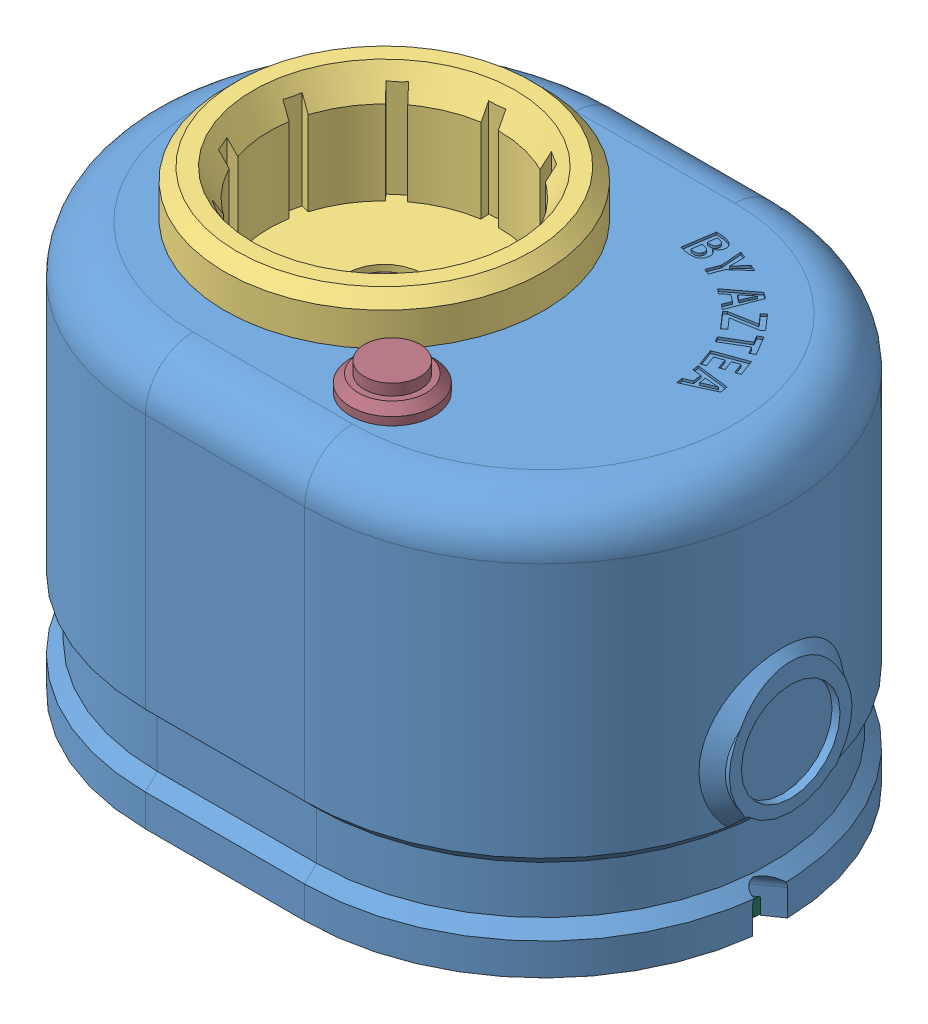
SolidWorks assembly Assem, configuration Default. Lengths in mm.
Overall size (81.48 58.5 65.83).
19 component instances, 16 part files, 39 mates.
Components (placement in the parent):
- Shell-1: Shell [Default] at origin size (81.48 51 60)
- deep groove ball bearings gb-1: deep groove ball bearings gb [Rolling bearings 619-5 GB 276-94] at (0 19 0) x (0 1 0) z (-0.056348 0 0.998411) size (4 13 13)
- deep groove ball bearings gb-2: deep groove ball bearings gb [Rolling bearings 619-9 GB 276-94] at (0 33 0) x (0 1 0) z (0 0 1) size (6 20 20)
- Base-1: Base [Default] at (0 30 0) x (-0.082229 0 -0.996613) z (0.996613 0 -0.082229) size (40 27 40)
- Screw-1: Screw [Default] at (0 39 0) size (9 36.5 9)
- Motor-2: Motor [Default] at (31 22.2 0) x (-1 0 0) z (0 0 -1) size (32 35.4 47)
- Crank_M-1: Crank_M [Default] at (23 9 0) x (-0.933743 0 -0.357945) z (0.357945 0 -0.933743) size (18.5 7 10)
- Rocker_B-1: Rocker_B [Default] at (0 7 0) x (-0.082229 0 -0.996613) z (0.996613 0 -0.082229) size (31 10 12)
- Link-1: Link [Default] at (-1.5624 3 -18.9357) x (0.72285 0 0.691005) z (-0.691005 0 0.72285) size (33 6 10)
- ScrewM3-1: ScrewM3 [Default] at (-1.5624 6.5 -18.9357) x (0.991725 0 -0.128382) z (-0.128382 0 -0.991725) size (7 14.5 7)
- ScrewM3-2: ScrewM3 [Default] at (15.0632 6.5 -3.0425) x (-0.517907 0 -0.855437) z (-0.855437 0 0.517907) size (7 14.5 7)
- NutM3_FS-1: NutM3_FS [Default] at (15.0632 12 -3.0425) x (0.776861 0 -0.629672) z (0.629672 0 0.776861) size (6.29 3.9 5.5)
- NutM3_FS-2: NutM3_FS [Default] at (-1.5624 13 -18.9357) x (0.904207 0 0.427094) z (-0.427094 0 0.904207) size (6.29 3.9 5.5)
- NutM4_FS-2: NutM4_FS [Default] at (0 12 0) x (0.821978 0 -0.569519) z (-0.569519 0 -0.821978) size (8.02 5 7)
- Bushing-1: Bushing [Default] at (0 -13.7901 0) x (0.95303 0 0.302877) z (-0.302877 0 0.95303) size (12.8 9 12.8)
- Switch-1: Switch [Default] at (19 54.4 18) x (0 -1 0) z (-0.091572 0 0.995798) size (21.9 10.5 10.5)
- NutM8-2: NutM8 [Default] at (19 49 18) x (0.969422 0 -0.245401) z (0 -1 0) size (9.9 11.43 2.2)
- BasePlate-1: BasePlate [Default] at origin size (75.8 22 55.8)
- BaseSupport-1: BaseSupport [Default] at origin size (59.67 1.5 46.11)
Mates (geometry in assembly coordinates):
- Concentric1: concentric anti-aligned: cylinder of Shell-1 through (0 36 0) axis (0 1 0) radius 6.5; cylinder of Rolling bearings 619-5 GB 276-94-1 through (0 10.2893 0) axis (0 -1 0) radius 6.5
- Coincident1: coincident anti-aligned: plane of Shell-1 through (-6.5 21 0) normal (0 -1 0); plane of Rolling bearings 619-5 GB 276-94-1 through (-6.4897 21 -0.3663) normal (0 1 0)
- Concentric2: concentric anti-aligned: cylinder of Shell-1 through (0 36 0) axis (0 1 0) radius 10; cylinder of Rolling bearings 619-9 GB 276-94-1 through (0 24.2893 0) axis (0 -1 0) radius 10
- Coincident2: coincident anti-aligned: plane of Shell-1 through (-8 30 0) normal (0 1 0); plane of Rolling bearings 619-9 GB 276-94-1 through (-10 30 0) normal (0 -1 0)
- Concentric3: concentric anti-aligned: cylinder of Shell-1 through (0 -9 0) axis (0 1 0) radius 18; cylinder of Base-1 through (0 30 0) axis (0 -1 0) radius 14.5
- Coincident3: coincident anti-aligned: plane of Rolling bearings 619-9 GB 276-94-1 through (-4.5 36 0) normal (0 1 0); plane of Base-1 through (0.5345 36 6.478) normal (0 -1 0)
- Concentric4: concentric anti-aligned: cylinder of Base-1 through (0 30 0) axis (0 -1 0) radius 2.5; cylinder of Screw-1 through (0 42.5 0) axis (0 1 0) radius 2.5
- Coincident4: coincident anti-aligned: plane of Base-1 through (0.2056 39 2.4915) normal (0 1 0); plane of Screw-1 through (-4.5 39 0) normal (0 -1 0)
- Concentric8: concentric aligned: cylinder of Motor-2 through (23 22.2 0) axis (0 1 0) radius 2.5; cylinder of Crank_M-1 through (23 12 0) axis (0 1 0) radius 2.5
- Coincident8: coincident anti-aligned: plane of Motor-2 through (25.5 12 0) normal (0 -1 0); plane of Crank_M-1 through (23 12 0) normal (0 1 0)
- Distance1: distance = 31 mm anti-aligned: plane of Motor-2 through (31 22.2 0) normal (-1 0 0)
- Distance2: distance = 1.6 mm anti-aligned: plane of Motor-2 through (43.25 47.4 0) normal (0 1 0); plane of Shell-1 through (0 49 0) normal (0 -1 0)
- Coincident12: coincident anti-aligned: plane of Motor-2 through (31 22.2 0) normal (0 0 -1)
- Concentric9: concentric anti-aligned: cylinder of Screw-1 through (0 42.5 0) axis (0 1 0) radius 2.5; cylinder of Rocker_B-1 through (0 7 0) axis (0 -1 0) radius 2.55
- Coincident13: coincident anti-aligned: plane of Rolling bearings 619-5 GB 276-94-1 through (-3.8272 17 -0.216) normal (0 -1 0); plane of Rocker_B-1 through (0 17 0) normal (0 1 0)
- Concentric10: concentric aligned: cylinder of Rocker_B-1 through (-1.5624 7 -18.9357) axis (0 -1 0) radius 2.075; cylinder of Link-1 through (-1.5624 9 -18.9357) axis (0 -1 0) radius 5
- Concentric11: concentric aligned: cylinder of Crank_M-1 through (15.0632 9 -3.0425) axis (0 -1 0) radius 2.075; cylinder of Link-1 through (15.0632 9 -3.0425) axis (0 -1 0) radius 5
- Concentric12: concentric aligned: cylinder of Link-1 through (-1.5624 3 -18.9357) axis (0 -1 0) radius 2.075; cylinder of ScrewM3-1 through (-1.5624 3 -18.9357) axis (0 -1 0) radius 2
- Coincident15: coincident anti-aligned: plane of Link-1 through (-4.273 6.5 -21.5269) normal (0 -1 0); plane of ScrewM3-1 through (-5.0334 6.5 -18.4863) normal (0 1 0)
- Concentric13: concentric aligned: cylinder of Link-1 through (15.0632 3 -3.0425) axis (0 -1 0) radius 2.075; cylinder of ScrewM3-2 through (15.0632 3 -3.0425) axis (0 -1 0) radius 2
- Coincident16: coincident anti-aligned: plane of Link-1 through (12.3525 6.5 -5.6338) normal (0 -1 0); plane of ScrewM3-2 through (16.8759 6.5 -0.0485) normal (0 1 0)
- Concentric14: concentric aligned: cylinder of ScrewM3-1 through (-1.5624 3 -18.9357) axis (0 -1 0) radius 1.5; cylinder of NutM3_FS-2 through (-1.5624 13 -18.9357) axis (0 -1 0) radius 1.25
- Coincident17: coincident anti-aligned: plane of Rocker_B-1 through (-1.3568 13 -16.4441) normal (0 1 0); plane of NutM3_FS-2 through (-1.5624 13 -18.9357) normal (0 -1 0)
- Concentric15: concentric aligned: cylinder of ScrewM3-2 through (15.0632 3 -3.0425) axis (0 -1 0) radius 1.5; cylinder of NutM3_FS-1 through (15.0632 12 -3.0425) axis (0 -1 0) radius 1.25
- Parallel2: parallel aligned: plane of Rocker_B-1 through (-5.9797 17 0.4934) normal (-0.996613 0 0.082229); plane of NutM3_FS-2 through (-4.4336 15.4 -20.2919) normal (-0.996613 0 0.082229)
- Parallel3: parallel aligned: plane of Crank_M-1 through (21.2103 16 4.6687) normal (-0.357945 0 0.933743); plane of NutM3_FS-1 through (12.5963 14.4 -1.0431) normal (-0.357945 0 0.933743)
- Concentric17: concentric aligned: cylinder of Screw-1 through (0 42.5 0) axis (0 1 0) radius 2; cylinder of NutM4_FS-2 through (0 12 0) axis (0 1 0) radius 1.65
- Parallel4: parallel aligned: plane of Rocker_B-1 through (-5.9797 17 0.4934) normal (-0.996613 0 0.082229); plane of NutM4_FS-2 through (-3.322 9.1 2.3017) normal (-0.996613 0 0.082229)
- Coincident24: coincident aligned: plane of Rocker_B-1 through (0 7 0) normal (0 -1 0); plane of NutM4_FS-2 through (0 7 0) normal (0 -1 0)
- Coincident27: coincident anti-aligned: plane of Crank_M-1 through (23 9 0) normal (0 -1 0); plane of Link-1 through (-1.5624 9 -18.9357) normal (0 1 0)
- Coincident28: coincident anti-aligned: plane of Crank_M-1 through (23 12 0) normal (0 1 0); plane of NutM3_FS-1 through (15.0632 12 -3.0425) normal (0 -1 0)
- Coincident29: coincident anti-aligned: plane of Shell-1 through (0 51 0) normal (0 1 0); plane of Switch-1 through (22.9832 51 18.3663) normal (0 -1 0)
- Concentric18: concentric aligned: cylinder of Switch-1 through (19 54.4 18) axis (0 1 0) radius 4; cylinder of Nut-2 through (19 46.8 18) axis (0 1 0) radius 3.35
- Coincident30: coincident anti-aligned: plane of Shell-1 through (0 49 0) normal (0 -1 0); plane of Nut-2 through (19 49 18) normal (0 1 0)
- Parallel6: parallel aligned: plane of Shell-1 through (0 51 0) normal (0 1 0); plane of Switch-1 through (22.4853 54.4 18.3205) normal (0 1 0)
- Concentric19: concentric aligned: cylinder of Shell-1 through (19 -0.001 18) axis (0 1 0) radius 4.1; cylinder of Switch-1 through (19 54.4 18) axis (0 1 0) radius 4
- Concentric20: concentric anti-aligned: cylinder of Shell-1 through (0 36 0) axis (0 1 0) radius 9.5; cylinder of Bushing-1 through (0 -4 0) axis (0 -1 0) radius 6.4
- Coincident32: coincident anti-aligned: plane of Base-1 through (0.37 30 4.4848) normal (0 -1 0); plane of Bushing-1 through (-6.0994 30 -1.9384) normal (0 1 0)
- Coincident33: coincident aligned: plane of Base-1 through (0 30 0) normal (0.996613 0 -0.082229); plane of Rocker_B-1 through (0 7 0) normal (0.996613 0 -0.082229)
